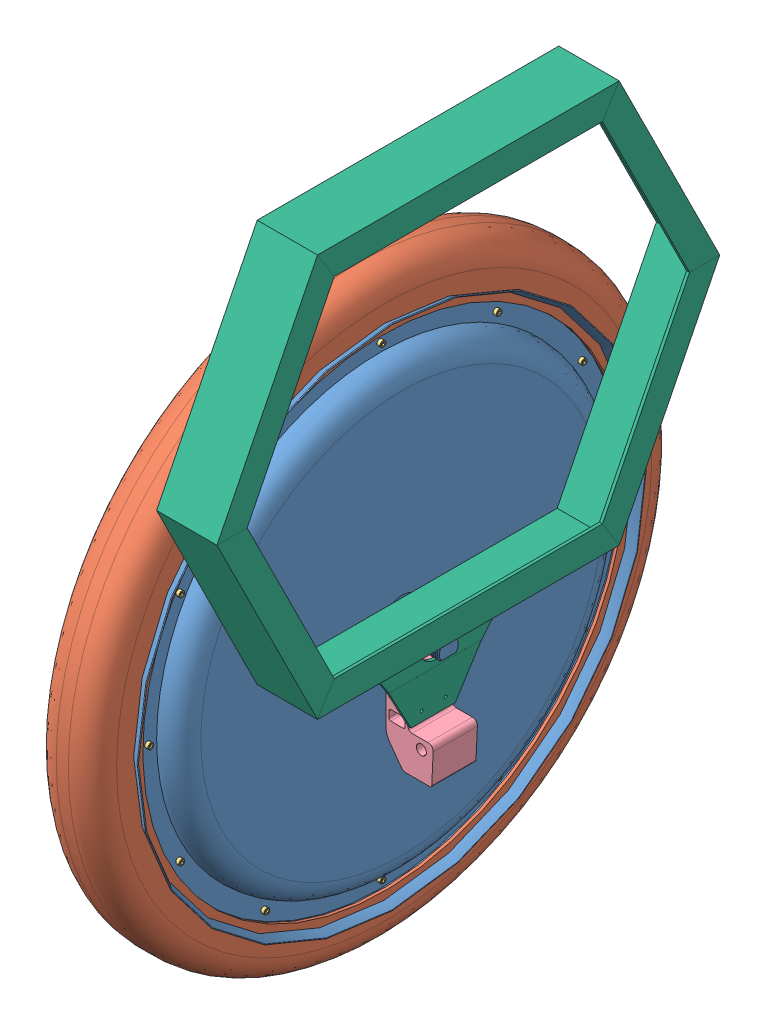
SolidWorks assembly euc0.6, configuration Default. Lengths in mm.
Overall size (364.75 830.02 810.04).
34 component instances, 9 part files, 57 mates.
Components (placement in the parent):
- wheel-1: wheel [Default] at origin size (217.51 810.04 810.04)
  - motor-1: motor [Default] at origin size (188.73 505.83 505.83)
  - tyre-1: tyre [Default] at (-29.8207 0 0) x (1 0 0) z (0 0.587098 0.809516) size (60 580 580)
  - socket head cap screw_ai-1: socket head cap screw_ai [HX-SHCS 0.138-40x0.188x0.188-N] at (29.5052 231 0) x (-1 0 0) z (0 0 -1) size (8.28 5.74 5.74)
  - socket head cap screw_ai-2: socket head cap screw_ai [HX-SHCS 0.138-40x0.188x0.188-N] at (29.5052 200.0519 -115.5) x (-1 0 0) z (0 -0.5 -0.866025) size (8.28 5.74 5.74)
  - socket head cap screw_ai-3: socket head cap screw_ai [HX-SHCS 0.138-40x0.188x0.188-N] at (29.5052 200.0519 115.5) x (-1 0 0) z (0 0.5 -0.866025) size (8.28 5.74 5.74)
  - socket head cap screw_ai-4: socket head cap screw_ai [HX-SHCS 0.138-40x0.188x0.188-N] at (29.5052 115.5 200.0519) x (-1 0 0) z (0 0.866025 -0.5) size (8.28 5.74 5.74)
  - socket head cap screw_ai-5: socket head cap screw_ai [HX-SHCS 0.138-40x0.188x0.188-N] at (29.5052 0 231) x (-1 0 0) z (0 1 0) size (8.28 5.74 5.74)
  - socket head cap screw_ai-6: socket head cap screw_ai [HX-SHCS 0.138-40x0.188x0.188-N] at (29.5052 -115.5 200.0519) x (-1 0 0) z (0 0.866025 0.5) size (8.28 5.74 5.74)
  - socket head cap screw_ai-7: socket head cap screw_ai [HX-SHCS 0.138-40x0.188x0.188-N] at (29.5052 -200.0519 115.5) x (-1 0 0) z (0 0.5 0.866025) size (8.28 5.74 5.74)
  - socket head cap screw_ai-8: socket head cap screw_ai [HX-SHCS 0.138-40x0.188x0.188-N] at (29.5052 -231 0) x (-1 0 0) z (0 0 1) size (8.28 5.74 5.74)
  - socket head cap screw_ai-9: socket head cap screw_ai [HX-SHCS 0.138-40x0.188x0.188-N] at (29.5052 -200.0519 -115.5) x (-1 0 0) z (0 -0.5 0.866025) size (8.28 5.74 5.74)
  - socket head cap screw_ai-10: socket head cap screw_ai [HX-SHCS 0.138-40x0.188x0.188-N] at (29.5052 -115.5 -200.0519) x (-1 0 0) z (0 -0.866025 0.5) size (8.28 5.74 5.74)
  - socket head cap screw_ai-11: socket head cap screw_ai [HX-SHCS 0.138-40x0.188x0.188-N] at (29.5052 0 -231) x (-1 0 0) z (0 -1 0) size (8.28 5.74 5.74)
  - socket head cap screw_ai-12: socket head cap screw_ai [HX-SHCS 0.138-40x0.188x0.188-N] at (29.5052 115.5 -200.0519) x (-1 0 0) z (0 -0.866025 -0.5) size (8.28 5.74 5.74)
  - socket head cap screw_ai-13: socket head cap screw_ai [HX-SHCS 0.138-40x0.188x0.188-N] at (-29.5052 231 0) size (8.28 5.74 5.74)
  - socket head cap screw_ai-14: socket head cap screw_ai [HX-SHCS 0.138-40x0.188x0.188-N] at (-29.5052 200.0519 -115.5) x (1 0 0) z (0 0.5 0.866025) size (8.28 5.74 5.74)
  - socket head cap screw_ai-15: socket head cap screw_ai [HX-SHCS 0.138-40x0.188x0.188-N] at (-29.5052 200.0519 115.5) x (1 0 0) z (0 -0.5 0.866025) size (8.28 5.74 5.74)
  - socket head cap screw_ai-16: socket head cap screw_ai [HX-SHCS 0.138-40x0.188x0.188-N] at (-29.5052 115.5 200.0519) x (1 0 0) z (0 -0.866025 0.5) size (8.28 5.74 5.74)
  - socket head cap screw_ai-17: socket head cap screw_ai [HX-SHCS 0.138-40x0.188x0.188-N] at (-29.5052 0 231) x (1 0 0) z (0 -1 0) size (8.28 5.74 5.74)
  - socket head cap screw_ai-18: socket head cap screw_ai [HX-SHCS 0.138-40x0.188x0.188-N] at (-29.5052 -115.5 200.0519) x (1 0 0) z (0 -0.866025 -0.5) size (8.28 5.74 5.74)
  - socket head cap screw_ai-19: socket head cap screw_ai [HX-SHCS 0.138-40x0.188x0.188-N] at (-29.5052 -200.0519 115.5) x (1 0 0) z (0 -0.5 -0.866025) size (8.28 5.74 5.74)
  - socket head cap screw_ai-20: socket head cap screw_ai [HX-SHCS 0.138-40x0.188x0.188-N] at (-29.5052 -231 0) x (1 0 0) z (0 0 -1) size (8.28 5.74 5.74)
  - socket head cap screw_ai-21: socket head cap screw_ai [HX-SHCS 0.138-40x0.188x0.188-N] at (-29.5052 -200.0519 -115.5) x (1 0 0) z (0 0.5 -0.866025) size (8.28 5.74 5.74)
  - socket head cap screw_ai-22: socket head cap screw_ai [HX-SHCS 0.138-40x0.188x0.188-N] at (-29.5052 -115.5 -200.0519) x (1 0 0) z (0 0.866025 -0.5) size (8.28 5.74 5.74)
  - socket head cap screw_ai-23: socket head cap screw_ai [HX-SHCS 0.138-40x0.188x0.188-N] at (-29.5052 0 -231) x (1 0 0) z (0 1 0) size (8.28 5.74 5.74)
  - socket head cap screw_ai-24: socket head cap screw_ai [HX-SHCS 0.138-40x0.188x0.188-N] at (-29.5052 115.5 -200.0519) x (1 0 0) z (0 0.866025 0.5) size (8.28 5.74 5.74)
  - pedal hanger1-1: pedal hanger1 [Default] at (128.9328 -140.4403 -75.0082) x (0.997537 -0.070149 0) z (-0.006861 -0.09757 0.995205) size (54.31 133.41 56.48)
  - pedal hanger2-1: pedal hanger2 [Default] at (-128.9328 -140.4403 75.0082) x (-0.997537 -0.070149 0) z (0.006861 -0.09757 -0.995205) size (54.31 133.41 56.48)
- mt60 fem-1: mt60 fem [Default] at (85.5155 -2.714 -4.2673) x (0 1 0) z (0.866025 0 -0.5) size (29 12 12.94) (hidden)
  - Мама-1: Мама [По умолчанию] at (18.214 0 0) x (0 0 -1) z (1 0 0) size (12.94 12 20)
  - Колпачек 2-1: Колпачек 2 [По умолчанию] at (35.714 0 0) x (0 0 -1) z (1 0 0) size (12.94 12 13) (hidden)
  - Деталь11-1: Деталь11 [По умолчанию] at (44.714 0 0) x (0 0 -1) z (1 0 0) size (8 7.46 6.5)
- Part1^euc0.6-1: Part1^euc0.6 [Default] at origin size (60 488.95 500) (virtual)
Mates (geometry in assembly coordinates):
- Parallel1: parallel anti-aligned: plane of Chassis-1/Internal chassis-1 through (0 28 0) normal (0 1 0); plane of mt60 fem-1/Copy of Мама^mt60 fem-1 through (90.0311 15.5 3.5538) normal (0 -1 0)
- Parallel2: parallel aligned: plane of Chassis-1/Internal chassis-1 through (57 28 288) normal (1 0 0); plane of mt60 fem-1/Copy of Мама^mt60 fem-1 through (93 29 3.5538) normal (1 0 0)
- Coincident3: coincident anti-aligned: plane of Chassis-1/Internal chassis-1 through (93 7.266 3.5) normal (-1 0 0); plane of mt60 fem-1/Copy of Мама^mt60 fem-1 through (93 29 3.5538) normal (1 0 0)
- Coincident4: coincident anti-aligned: plane of Chassis-1/Internal chassis-1 through (82.4378 7.266 2.5981) normal (0.5 0 -0.866025); plane of mt60 fem-1/Copy of Мама^mt60 fem-1 through (82.4845 29 2.625) normal (-0.5 0 0.866025)
- Coincident5: coincident aligned: plane of Chassis-1/Internal chassis-1 through (100 25 0) normal (0 -1 0); plane of mt60 fem-1/Copy of Мама^mt60 fem-1 through (83.9689 25 0.0538) normal (0 -1 0)
- Coincident18: coincident anti-aligned: plane of Chassis-1/Internal chassis-1 through (57 28 288) normal (1 0 0); plane of Battery1-1 through (57 187.8877 190.3024) normal (-1 0 0)
- Coincident23: coincident anti-aligned: plane of Chassis-1/Internal chassis-1 through (57 28 288) normal (1 0 0); plane of Battery2-2 through (57 212.7697 -24.9641) normal (-1 0 0)
- Parallel5: parallel aligned: plane of Chassis-1/Internal chassis-1 through (0 28 0) normal (0 1 0); plane of Battery1-1 through (75 187.8877 109.3024) normal (0 1 0)
- Parallel6: parallel aligned: plane of Chassis-1/Internal chassis-1 through (0 28 0) normal (0 1 0); plane of Battery2-2 through (75 212.7697 -105.9641) normal (0 1 0)
- InPlace2: in place: plane of ? through (57 28 288) normal (1 0 0); plane of ? through (57 0 0) normal (1 0 0); moOrthogonalPlaneRef_w of ? through (57 28 288) normal (1 0 0); plane of ? through (57 0 0) normal (0 1 0); plane of ? through (57 28 288) normal (1 0 0); plane of ? through (57 0 0) normal (0 0 -1); plane of ? through (57 28 288) normal (1 0 0); unknown of ?
- Coincident26: coincident aligned: plane of ?; plane of ?
- Coincident27: coincident aligned: moOrthogonalPlaneRef_w of Chassis-1/Internal chassis-1 through (57 0 0) normal (0 1 0); plane of Lid^euc0.2-2 through (57 0 0) normal (0 1 0)
- Coincident28: coincident anti-aligned: moOrthogonalPlaneRef_w of Chassis-1/Internal chassis-1 through (57 0 0) normal (0 0 1); plane of Lid^euc0.2-2 through (57 0 0) normal (0 0 -1)
- InPlace3: in place: plane of ? through (0 303.0294 0) normal (0 1 0); plane of ? through (0 303.0294 0) normal (0 1 0); plane of ? through (0 303.0294 0) normal (0 1 0); plane of ? through (0 303.0294 0) normal (0 0 -1); plane of ? through (0 303.0294 0) normal (0 1 0); plane of ? through (0 303.0294 0) normal (1 0 0); plane of ? through (0 303.0294 0) normal (0 1 0); unknown of ?
- Coincident1482: coincident aligned: plane of ?; plane of ?
- Coincident1483: coincident aligned: moOrthogonalPlaneRef_w of top chassis^euc0.2-1 through (0 303.0294 0) normal (0 0 -1); plane of Pcb plate^euc0.2-1 through (0 303.0294 0) normal (0 0 -1)
- Coincident1484: coincident anti-aligned: moOrthogonalPlaneRef_w of top chassis^euc0.2-1 through (0 303.0294 0) normal (-1 0 0); plane of Pcb plate^euc0.2-1 through (0 303.0294 0) normal (1 0 0)
- Coincident1488: coincident anti-aligned: plane of Pcb plate^euc0.2-1 through (-24 312.0294 76) normal (0 1 0); plane of pcb^euc0.2-1 through (0 312.0294 0) normal (0 -1 0)
- Coincident1489: coincident aligned: plane of Pcb plate^euc0.2-1 through (-40 307.0294 80) normal (0 0 1); plane of pcb^euc0.2-1 through (-28 315.0294 80) normal (0 0 1)
- Coincident1490: coincident anti-aligned: plane of Pcb plate^euc0.2-1 through (28 315.0294 -80) normal (-1 0 0); plane of pcb^euc0.2-1 through (28 315.0294 80) normal (1 0 0)
- Coincident1491: coincident anti-aligned: plane of Chassis-1/Internal chassis-1 through (57 28 288) normal (1 0 0); plane of Battery-2 through (57 183.6915 -26.6601) normal (-1 0 0)
- InPlace4: in place: plane of ? through (104 0 237.8048) normal (1 0 0); plane of ? through (104 0 0) normal (1 0 0); plane of ? through (104 0 237.8048) normal (1 0 0); plane of ? through (104 0 0) normal (0 1 0); plane of ? through (104 0 237.8048) normal (1 0 0); plane of ? through (104 0 0) normal (0 0 -1); plane of ? through (104 0 237.8048) normal (1 0 0); unknown of ?
- Coincident1493: coincident aligned: plane of ?; plane of ?
- Coincident1494: coincident aligned: moOrthogonalPlaneRef_w of Chassis^euc0.3-3 through (104 0 0) normal (0 1 0); plane of Lid^euc0.3-1 through (104 0 0) normal (0 1 0)
- Coincident1495: coincident anti-aligned: moOrthogonalPlaneRef_w of Chassis^euc0.3-3 through (104 0 0) normal (0 0 1); plane of Lid^euc0.3-1 through (104 0 0) normal (0 0 -1)
- Coincident1496: coincident anti-aligned: plane of Chassis^euc0.3-3 through (-104 0 237.8048) normal (-1 0 0); plane of Lid-2 through (-104 0 0) normal (1 0 0)
- Coincident1497: coincident aligned: plane of Chassis^euc0.3-3 through (-266.8954 375.6488 120.8782) normal (0 1 0); plane of Lid-2 through (-107 375.6488 120.8782) normal (0 1 0)
- Coincident1498: coincident aligned: plane of Chassis^euc0.3-3 through (0 0 237.8048) normal (0 0 1); plane of Lid-2 through (-107 -38.5515 237.8048) normal (0 0 1)
- Coincident1499: coincident anti-aligned: plane of Chassis^euc0.3-3 through (57 0 0) normal (1 0 0); plane of Battery-1 through (57 192.3346 205.2759) normal (-1 0 0)
- Coincident1500: coincident anti-aligned: plane of Chassis^euc0.3-3 through (57 0 0) normal (1 0 0); plane of Battery2-1 through (57 203.823 -30.8756) normal (-1 0 0)
- Coincident1501: coincident anti-aligned: plane of Chassis^euc0.3-3 through (-57 0 0) normal (-1 0 0); plane of Battery3-1 through (-188.3607 187.3052 -82.7053) normal (1 0 0)
- Coincident1502: coincident anti-aligned: plane of Chassis^euc0.3-3 through (-57 0 0) normal (-1 0 0); plane of Battery4-1 through (-168.6008 189.7472 162.2406) normal (1 0 0)
- Parallel8: parallel aligned: plane of wheel-1/motor-1 through (48 0 0) normal (1 0 0); plane of Chassis^euc0.5-4 through (128.9328 -140.4403 22) normal (1 0 0)
- Coincident1509: coincident: unknown of wheel-1
- Coincident1510: coincident: unknown of wheel-1
- Parallel9: parallel aligned: plane of wheel-1/pedal hanger1-1 through (74 -75.003 22) normal (0 0 1)
- InPlace6: in place: plane of ? through (0 0 0) normal (1 0 0); plane of ? through (0 0 0) normal (1 0 0); plane of ? through (0 0 0) normal (1 0 0); plane of ? through (0 0 0) normal (0 1 0); plane of ? through (0 0 0) normal (1 0 0); plane of ? through (0 0 0) normal (0 0 -1); plane of ? through (48 0 0) normal (1 0 0); unknown of ?
- Coincident1512: coincident aligned: plane of ?; plane of ?
- Coincident1513: coincident aligned: moOrthogonalPlaneRef_w of wheel-1/motor-1 through (48 0 0) normal (0 1 0); plane of Chassis^euc0.5-5 through (48 0 0) normal (0 1 0)
- Coincident1514: coincident anti-aligned: moOrthogonalPlaneRef_w of wheel-1/motor-1 through (48 0 0) normal (0 0 1); plane of Chassis^euc0.5-5 through (48 0 0) normal (0 0 -1)
- Coincident1515: coincident: unknown of wheel-1
- Parallel11: parallel aligned: plane of wheel-1/motor-1 through (48 0 0) normal (1 0 0)
- InPlace7: in place: plane of ? through (57 0 0) normal (1 0 0); plane of ? through (57 0 0) normal (1 0 0); plane of ? through (57 0 0) normal (1 0 0); plane of ? through (57 0 0) normal (0 1 0); plane of ? through (57 0 0) normal (1 0 0); plane of ? through (57 0 0) normal (0 0 -1); plane of ? through (57 0 0) normal (1 0 0); unknown of ?
- Coincident1517: coincident aligned: plane of ?; plane of ?
- Coincident1518: coincident aligned: moOrthogonalPlaneRef_w of Chassis^euc0.5-5 through (57 0 0) normal (0 1 0); plane of Lid^euc0.5-1 through (57 0 0) normal (0 1 0)
- Coincident1519: coincident anti-aligned: moOrthogonalPlaneRef_w of Chassis^euc0.5-5 through (57 0 0) normal (0 0 1); plane of Lid^euc0.5-1 through (57 0 0) normal (0 0 -1)
- Coincident1520: coincident anti-aligned: plane of Chassis^euc0.5-5 through (-104 25 25) normal (-1 0 0); plane of Lid^euc0.5-2 through (-104 0 0) normal (1 0 0)
- Coincident1521: coincident aligned: plane of Chassis^euc0.5-5 through (57 -37.635 227.577) normal (0 0 1); plane of Lid^euc0.5-2 through (-107 -37.635 227.577) normal (0 0 1)
- Coincident1522: coincident aligned: plane of Chassis^euc0.5-5 through (-248.0003 359.3102 131.1444) normal (0 1 0); plane of Lid^euc0.5-2 through (-107 359.3102 131.1444) normal (0 1 0)
- InPlace8: in place: plane of ? through (104 25 25) normal (1 0 0); plane of ? through (104 0 0) normal (1 0 0); plane of ? through (104 25 25) normal (1 0 0); plane of ? through (104 0 0) normal (0 1 0); plane of ? through (104 25 25) normal (1 0 0); plane of ? through (104 0 0) normal (0 0 -1); plane of ? through (104 25 25) normal (1 0 0); unknown of ?
- Coincident1523: coincident aligned: plane of ?; plane of ?
- Coincident1524: coincident aligned: moOrthogonalPlaneRef_w of Chassis^euc0.5-5 through (104 0 0) normal (0 1 0); plane of Lid^euc0.5-3 through (104 0 0) normal (0 1 0)
- Coincident1525: coincident anti-aligned: moOrthogonalPlaneRef_w of Chassis^euc0.5-5 through (104 0 0) normal (0 0 1); plane of Lid^euc0.5-3 through (104 0 0) normal (0 0 -1)
- Coincident1526: coincident anti-aligned: plane of Chassis^euc0.5-5 through (-104 25 25) normal (-1 0 0); plane of Lid^euc0.5-4 through (-104 0 0) normal (1 0 0)
- Coincident1527: coincident aligned: plane of Chassis^euc0.5-5 through (57 -37.635 227.577) normal (0 0 1); plane of Lid^euc0.5-4 through (-107 -37.635 227.577) normal (0 0 1)
- Coincident1528: coincident aligned: plane of Chassis^euc0.5-5 through (-248.0003 359.3102 131.1444) normal (0 1 0); plane of Lid^euc0.5-4 through (-107 359.3102 131.1444) normal (0 1 0)
- Coincident1533: coordinate: unknown of Part1^euc0.6-1
